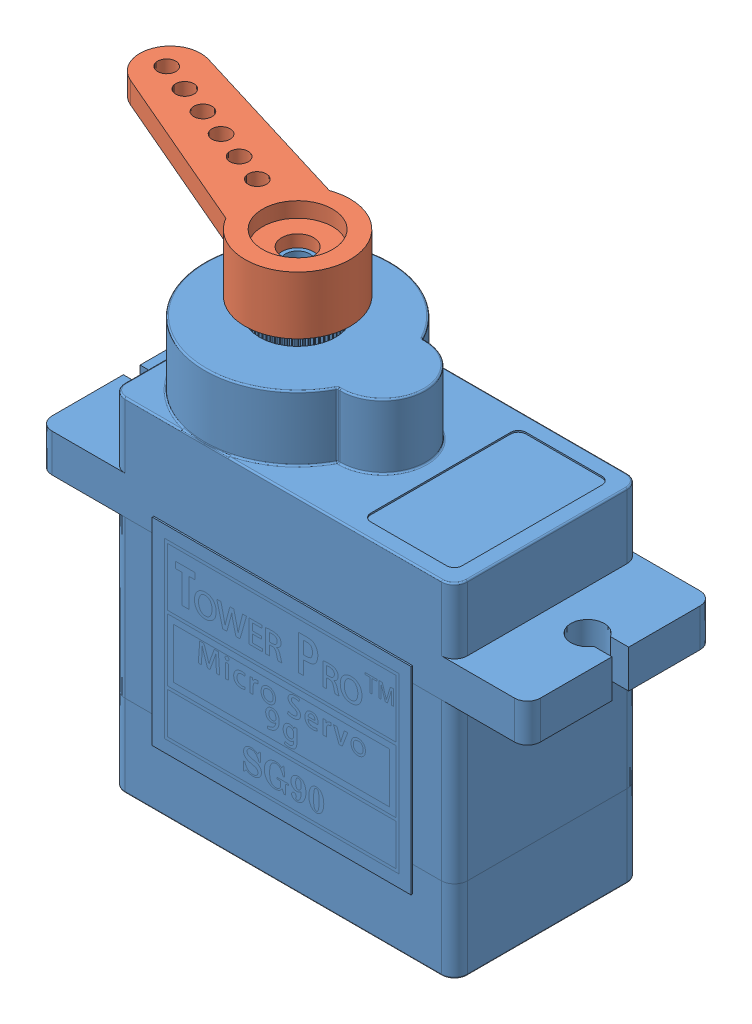
SolidWorks assembly SG90 - Micro Servo Assembly, configuration Default. Lengths in mm.
Overall size (37.46 31.75 14.96).
2 component instances, 2 part files, 2 mates.
Components (placement in the parent):
- SG90 - Micro Servo 9g - Tower Pro.1-2: SG90 - Micro Servo 9g - Tower Pro.1 [Peça] at origin size (32.1 29.95 12.4)
- SG90 - Micro Servo 9g - Tower Pro.2-2: SG90 - Micro Servo 9g - Tower Pro.2 [Peça] at (-5.15 21.1 0) x (0.939036 0 0.343818) z (-0.343818 0 0.939036) size (19.5 3.8 6.9)
Mates (geometry in assembly coordinates):
- Coincident2: coincident anti-aligned: plane of SG90 - Micro Servo 9g - Tower Pro.1-2 through (-5.15 19.3 0) normal (0 1 0); plane of SG90 - Micro Servo 9g - Tower Pro.2-2 through (-5.15 19.3 0) normal (0 -1 0)
- Concentric1: concentric anti-aligned: circle of SG90 - Micro Servo 9g - Tower Pro.1-2; circle of SG90 - Micro Servo 9g - Tower Pro.2-2
